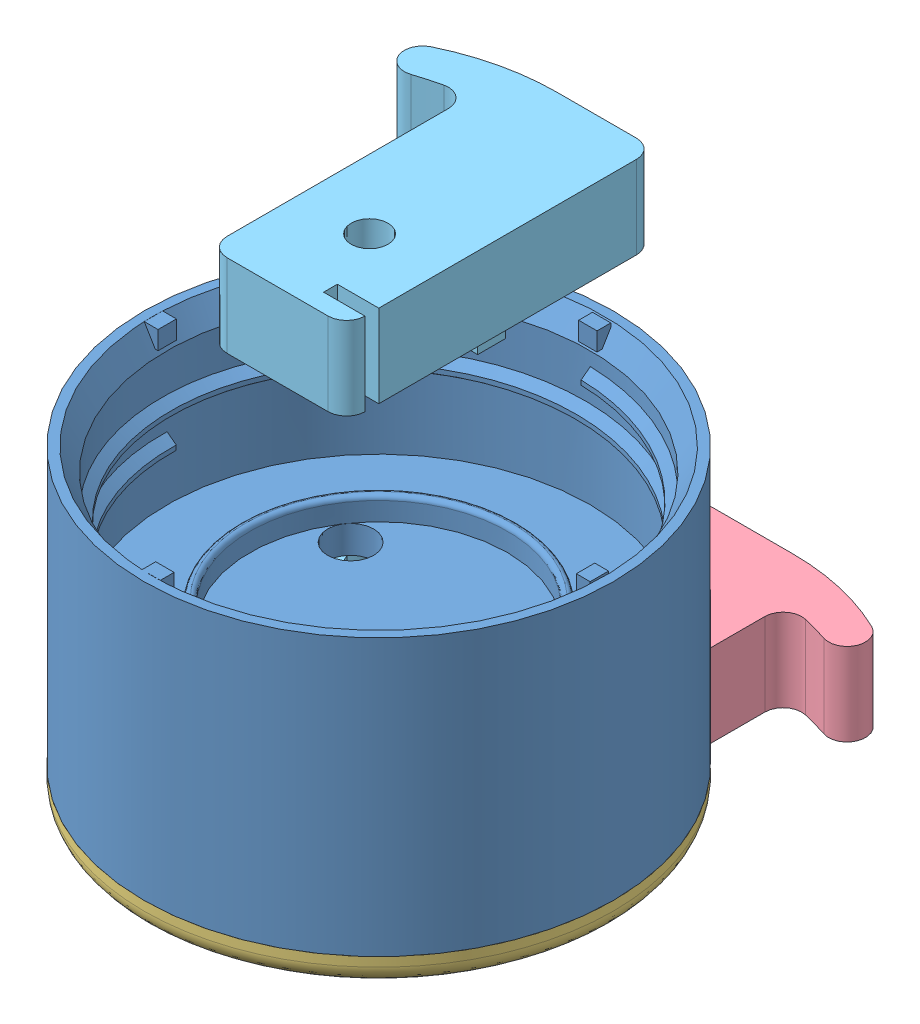
SolidWorks assembly 定量调味罐整体V1.0, configuration 默认. Lengths in mm.
Overall size (51 44.5 57.88).
6 component instances, 5 part files, 12 mates.
Components (placement in the parent):
- 定量调味罐V4.0-1: 定量调味罐V4.0 [默认] at (-69.7636 -6.7813 0) size (51 30.14 51)
- 弹簧-1: 弹簧 [默认] at (-60.2636 -11.7813 18.5472) x (-1 0 0) z (0 -1 0) size (15.83 16.57 7.24)
- 盖子-1: 盖子 [默认] at (-69.7636 -19.7813 0) size (51 3.5 51)
- 弹簧-2: 弹簧 [默认] at (-79.2636 -11.7813 18.5472) x (-1 0 0) z (0 -1 0) size (15.83 16.57 7.24)
- 定量调味罐V4.0_按键_5mm-1: 定量调味罐V4.0_按键_5mm [默认] at (-57.1464 -15.7813 -32.3839) x (-1 0 0) z (0 0 -1) size (22.88 10.5 33.5)
- 定量调味罐V4.0_按键_4mm-1: 定量调味罐V4.0_按键_4mm [默认] at (-82.3808 24.2187 -32.0101) x (1 0 0) z (0 0 -1) size (22.88 40 33.5)
Mates (geometry in assembly coordinates):
- 重合2: coincident aligned: plane of 定量调味罐V4.0-1 through (-69.7636 -16.7813 18.5472) normal (0 0 -1); plane of 弹簧-1 through (-60.2636 -11.7813 18.5472) normal (0 0 -1)
- 距离1: distance = 5 mm aligned: plane of 定量调味罐V4.0-1 through (-69.7636 -6.7813 0) normal (0 -1 0); plane of 弹簧-1 through (-60.2636 -11.7813 18.5472) normal (0 -1 0)
- 距离2: distance = 8 mm aligned: plane of 定量调味罐V4.0-1 through (-52.2636 -16.7813 0) normal (-1 0 0); plane of 弹簧-1 through (-60.2636 -11.7813 18.5472) normal (-1 0 0)
- 重合8: coincident anti-aligned: plane of 定量调味罐V4.0-1 through (-69.7636 -16.7813 0) normal (0 -1 0); plane of 盖子-1 through (-69.7636 -16.7813 0) normal (0 1 0)
- 同心1: concentric aligned: circle of 定量调味罐V4.0-1; circle of 盖子-1
- 重合13: coincident aligned: plane of 定量调味罐V4.0-1 through (-69.7636 -16.7813 18.5472) normal (0 0 -1); plane of 弹簧-2 through (-79.2636 -11.7813 18.5472) normal (0 0 -1)
- 距离6: distance = 5 mm aligned: plane of 定量调味罐V4.0-1 through (-69.7636 -6.7813 0) normal (0 -1 0); plane of 弹簧-2 through (-79.2636 -11.7813 18.5472) normal (0 -1 0)
- 距离7: distance = 8 mm aligned: plane of 定量调味罐V4.0-1 through (-71.2636 -16.7813 0) normal (-1 0 0); plane of 弹簧-2 through (-79.2636 -11.7813 18.5472) normal (-1 0 0)
- 重合16: coincident anti-aligned: plane of 定量调味罐V4.0-1 through (-69.7636 -6.7813 0) normal (0 -1 0); plane of 定量调味罐V4.0_按键_5mm-1 through (-57.1464 -6.7813 -6.8839) normal (0 1 0)
- 距离8: distance = 0.5 mm anti-aligned: plane of 定量调味罐V4.0_按键_5mm-1 through (-67.7636 -6.7813 -0.8839) normal (-1 0 0); plane of 定量调味罐V4.0-1 through (-68.2636 -16.7813 0) normal (1 0 0)
- 重合18: coincident anti-aligned: plane of 定量调味罐V4.0-1 through (-69.7636 -6.7813 0) normal (0 -1 0); plane of 定量调味罐V4.0_按键_4mm-1 through (-82.3808 -6.7813 -6.5101) normal (0 1 0)
- 距离9: distance = 0.5 mm anti-aligned: plane of 定量调味罐V4.0_按键_4mm-1 through (-71.7636 -6.7813 -0.5101) normal (1 0 0); plane of 定量调味罐V4.0-1 through (-71.2636 -16.7813 0) normal (-1 0 0)
